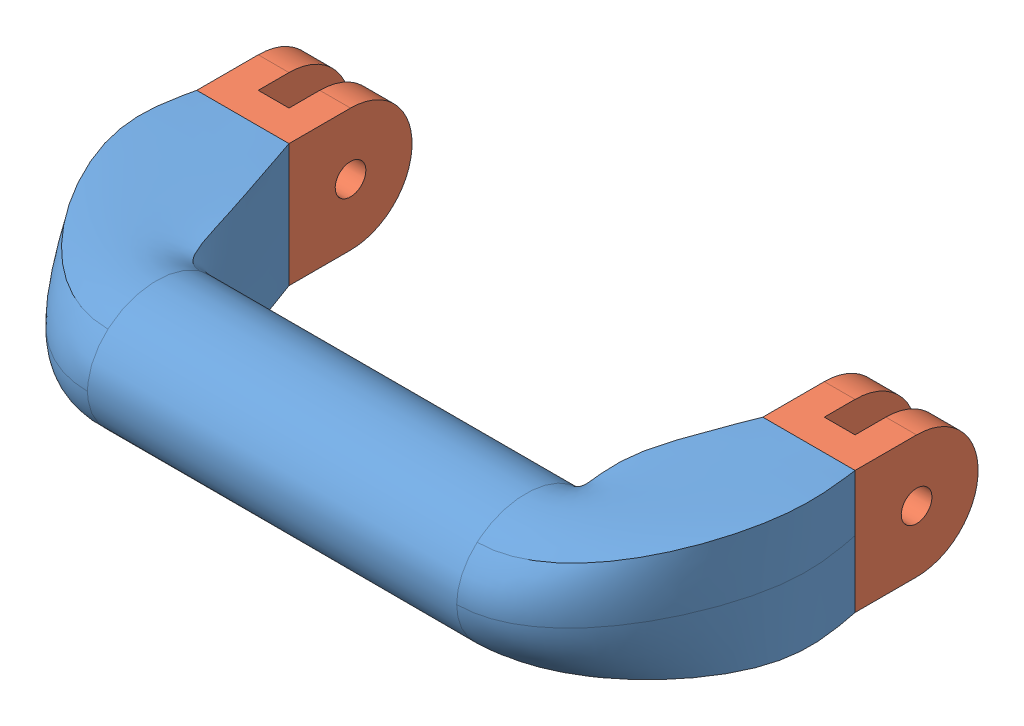
SolidWorks assembly handle, configuration Default. Lengths in mm.
Overall size (143.22 27.25 77.84).
3 component instances, 2 part files, 6 mates.
Components (placement in the parent):
- handle grip-1: handle grip [Default] at origin size (143.22 27.25 52.45)
- handle mount-1: handle mount [Default] at (58.42 0 -38.1) x (1 0 0) z (0 -1 0) size (19.05 25.4 25.4)
- handle mount-2: handle mount [Default] at (-58.42 0 -38.1) x (1 0 0) z (0 -1 0) size (19.05 25.4 25.4)
Mates (geometry in assembly coordinates):
- Coincident1: coincident: plane of handle grip-1 through (67.945 -12.7 -38.1) normal (0 0 -1); plane of handle mount-1 through (67.945 -12.7 -38.1) normal (0 0 1)
- Coincident2: coincident: line of handle grip-1 through (48.895 12.7 -38.1) axis (1 0 0); line of handle mount-1 through (67.945 12.7 -38.1) axis (-1 0 0)
- Coincident3: coincident: line of handle grip-1 through (48.895 -12.7 -38.1) axis (0 1 0); line of handle mount-1 through (48.895 12.7 -38.1) axis (0 -1 0)
- Coincident4: coincident: plane of handle grip-1 through (-67.945 -12.7 -38.1) normal (0 0 -1); plane of handle mount-2 through (-48.895 -12.7 -38.1) normal (0 0 1)
- Coincident5: coincident: line of handle grip-1 through (-48.895 12.7 -38.1) axis (-1 0 0); line of handle mount-2 through (-48.895 12.7 -38.1) axis (-1 0 0)
- Coincident6: coincident: line of handle grip-1 through (-48.895 -12.7 -38.1) axis (0 1 0); line of handle mount-2 through (-48.895 12.7 -38.1) axis (0 -1 0)
